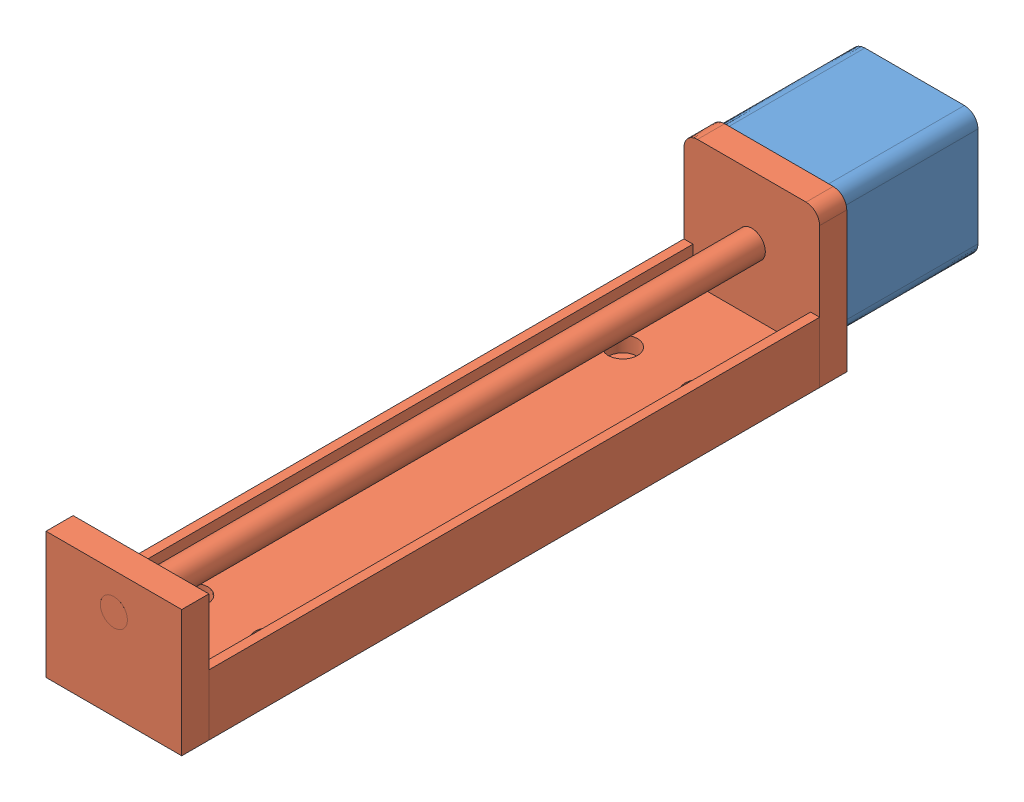
SolidWorks assembly 100mm Stroke Linear Axis, configuration Default. Lengths in mm.
Overall size (30 34 177).
2 component instances, 2 part files, 6 mates.
Components (placement in the parent):
- Nema 11-1: Nema 11 [Default] at origin size (28 29.5 30)
- Gantry-1: Gantry [Stroke 100mm] at origin size (30 34 147)
Mates (geometry in assembly coordinates):
- Coincident1: coincident aligned: plane of Nema 11-1 through (0 0 0) normal (0 0 1)
- Coincident2: coincident aligned: plane of Nema 11-1 through (0 0 0) normal (0 1 0)
- Coincident3: coincident aligned: plane of Nema 11-1 through (0 0 0) normal (1 0 0)
- Coincident4: coincident aligned: plane of Gantry-1 through (0 0 0) normal (0 0 1)
- Coincident5: coincident aligned: plane of Gantry-1 through (0 0 0) normal (0 1 0)
- Coincident6: coincident aligned: plane of Gantry-1 through (0 0 0) normal (1 0 0)
